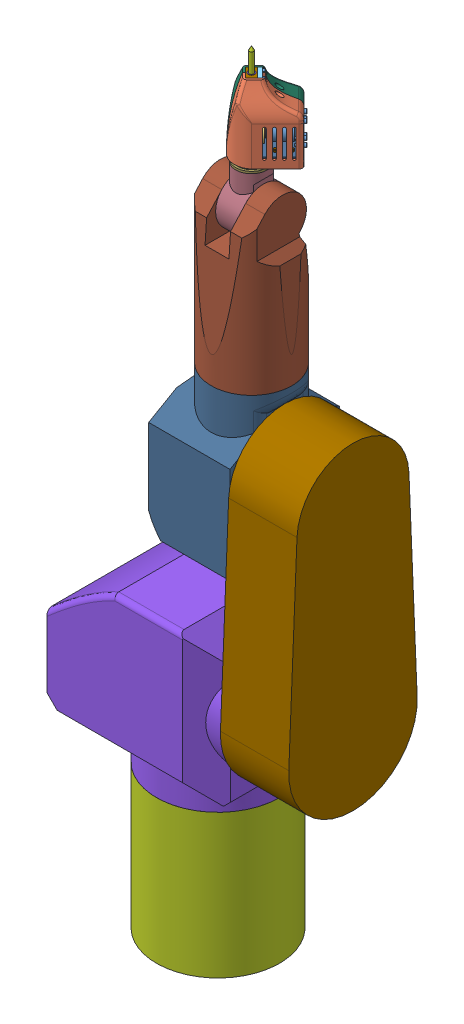
SolidWorks assembly Arm_2, configuration Default. Lengths in mm.
Overall size (341 1142 215.15).
59 component instances, 31 part files, 18 mates.
Components (placement in the parent):
- Assembly 1 _1_-1: Assembly 1 _1_ [Default] x (1 0 0) z (0 1 0) size (103.71 103.71 142.5)
  - Motor-1: Motor [Default] at (81.7405 32.7405 1038) x (0 0 1) z (-0.707107 0.707107 0) size (27.7 36 27.7)
  - MotorShaftMount-1: MotorShaftMount [Default] at (81.7405 32.7405 1038) x (0 0 1) z (-0.707107 0.707107 0) size (20 22.4 20)
  - MotorBearing-1: MotorBearing [Default] at (81.7405 32.7405 1038) x (0 0 1) z (-0.707107 0.707107 0) size (32 7 32)
  - MotorMount-1: MotorMount [Default] at (81.7405 32.7405 1038) x (0 0 1) z (-0.707107 0.707107 0) size (50 5 50)
  - ChiselBearingSupport-1: ChiselBearingSupport [Default] at (81.7405 32.7405 1038) x (0 0 1) z (-0.707107 0.707107 0) size (95.4 5 50)
  - ChiselOscillator-1: ChiselOscillator [Default] at (81.7405 32.7405 1038) x (0 0 1) z (-0.707107 0.707107 0) size (42 10.6 14)
  - Chisel-1: Chisel [Default] at (81.7405 32.7405 1038) x (0 0 1) z (-0.707107 0.707107 0) size (75 6.35 6.35)
  - SleeveBearingLarge-1: SleeveBearingLarge [Default] at (81.7405 32.7405 1038) x (0 0 1) z (-0.707107 0.707107 0) size (25.4 9.58 9.58)
  - ChiselShaftMount-1: ChiselShaftMount [Default] at (81.7405 32.7405 1038) x (0 0 1) z (-0.707107 0.707107 0) size (25.4 12.6 20)
  - BackSupport-1: BackSupport [Default] at (81.7405 32.7405 1038) x (0 0 1) z (-0.707107 0.707107 0) size (6 35 50)
  - FrontSupport-1: FrontSupport [Default] at (81.7405 32.7405 1038) x (0 0 1) z (-0.707107 0.707107 0) size (6 35 50)
  - 6mmBearing-1: 6mmBearing [Default] at (81.7405 32.7405 1038) x (0 0 1) z (-0.707107 0.707107 0) size (10 3 10)
  - 6mmBearing-2: 6mmBearing [Default] at (76.3636 27.3636 1038) x (0 0 1) z (-0.707107 0.707107 0) size (10 3 10)
  - Spacer-1: Spacer [Default] at (81.7405 32.7405 1038) x (0 0 1) z (-0.707107 0.707107 0) size (10 4.6 10)
  - SleeveBearingSmall-1: SleeveBearingSmall [Default] at (81.7405 32.7405 1038) x (0 0 1) z (-0.707107 0.707107 0) size (6.35 3.17 6.35)
  - SleeveBearingSmall-2: SleeveBearingSmall [Default] at (76.4874 27.4874 1038) x (0 0 1) z (-0.707107 0.707107 0) size (6.35 3.17 6.35)
  - ShellUpper-1: ShellUpper [Default] at (81.7405 32.7405 1038) x (0 0 1) z (-0.707107 0.707107 0) size (102.4 83.19 31.74)
  - MountingPlate-1: MountingPlate [Default] at (81.7405 32.7405 1038) x (0 0 1) z (-0.707107 0.707107 0) size (7 74.3 46)
  - Hex socket head cap screw ISO 4762-1: Hex socket head cap screw ISO 4762 [Default] at (60.1369 11.1369 1012.5) x (0.707107 0.707107 0) z (0 0 1) size (8.5 8.5 13)
  - Hex socket head cap screw ISO 4762-2: Hex socket head cap screw ISO 4762 [Default] at (37.8631 -11.1369 1012.5) x (0.707107 0.707107 0) z (0 0 1) size (8.5 8.5 13)
  - Hex socket head cap screw ISO 4762-3: Hex socket head cap screw ISO 4762 [Default] at (37.8631 11.1369 1012.5) x (0.707107 0.707107 0) z (0 0 1) size (8.5 8.5 13)
  - Hex socket head cap screw ISO 4762-4: Hex socket head cap screw ISO 4762 [Default] at (60.1369 -11.1369 1012.5) x (0.707107 0.707107 0) z (0 0 1) size (8.5 8.5 13)
  - Hex socket head cap screw ISO 4762-1-1: Hex socket head cap screw ISO 4762-1 [Default] at (56.41 27.209 1001) x (0.707107 0.707107 0) z (0 0 -1) size (8.5 8.5 21)
  - Hex socket head cap screw ISO 4762-1-2: Hex socket head cap screw ISO 4762-1 [Default] at (88.6861 19.8871 1001) x (0.707107 0.707107 0) z (0 0 -1) size (8.5 8.5 21)
  - Hex socket head cap screw ISO 4762-1-3: Hex socket head cap screw ISO 4762-1 [Default] at (68.8871 39.6861 1001) x (0.707107 0.707107 0) z (0 0 -1) size (8.5 8.5 21)
  - Hex socket head cap screw ISO 4762-1-4: Hex socket head cap screw ISO 4762-1 [Default] at (76.209 7.41 1001) x (0.707107 0.707107 0) z (0 0 -1) size (8.5 8.5 21)
  - Hex socket head cap screw ISO 4762-2-1: Hex socket head cap screw ISO 4762-2 [Default] at (71.841 53.9537 1016) x (0 0 1) z (0.707107 0.707107 0) size (5.5 5.5 13)
  - Hex socket head cap screw ISO 4762-2-2: Hex socket head cap screw ISO 4762-2 [Default] at (77.1443 52.893 1038) x (0 0 1) z (0.707107 0.707107 0) size (5.5 5.5 13)
  - Hex socket head cap screw ISO 4762-2-3: Hex socket head cap screw ISO 4762-2 [Default] at (54.1633 15.0628 1105.4) x (0 0 1) z (0.707107 0.707107 0) size (5.5 5.5 13)
  - Hex socket head cap screw ISO 4762-2-4: Hex socket head cap screw ISO 4762-2 [Default] at (83.3314 46.7058 1053.1554) x (0 0 1) z (0.707107 0.707107 0) size (5.5 5.5 13)
  - Hex socket head cap screw ISO 4762-2-5: Hex socket head cap screw ISO 4762-2 [Default] at (64.0628 5.1633 1086) x (0 0 1) z (0.707107 0.707107 0) size (5.5 5.5 13)
  - Hex socket head cap screw ISO 4762-2-6: Hex socket head cap screw ISO 4762-2 [Default] at (83.3314 46.7058 1022.8446) x (0 0 1) z (0.707107 0.707107 0) size (5.5 5.5 13)
  - Hex socket head cap screw ISO 4762-2-7: Hex socket head cap screw ISO 4762-2 [Default] at (64.0628 5.1633 1105.4) x (0 0 1) z (0.707107 0.707107 0) size (5.5 5.5 13)
  - Hex socket head cap screw ISO 4762-2-8: Hex socket head cap screw ISO 4762-2 [Default] at (101.893 28.1443 1038) x (0 0 1) z (0.707107 0.707107 0) size (5.5 5.5 13)
  - Hex socket head cap screw ISO 4762-2-9: Hex socket head cap screw ISO 4762-2 [Default] at (54.1633 15.0628 1086) x (0 0 1) z (0.707107 0.707107 0) size (5.5 5.5 13)
  - Hex socket head cap screw ISO 4762-2-10: Hex socket head cap screw ISO 4762-2 [Default] at (95.7058 34.3314 1053.1554) x (0 0 1) z (0.707107 0.707107 0) size (5.5 5.5 13)
  - Hex socket head cap screw ISO 4762-2-11: Hex socket head cap screw ISO 4762-2 [Default] at (35.7785 17.8912 1060) x (0 0 1) z (-0.707107 -0.707107 0) size (5.5 5.5 13)
  - Hex socket head cap screw ISO 4762-2-12: Hex socket head cap screw ISO 4762-2 [Default] at (95.7058 34.3314 1022.8446) x (0 0 1) z (0.707107 0.707107 0) size (5.5 5.5 13)
  - Hex socket head cap screw ISO 4762-2-13: Hex socket head cap screw ISO 4762-2 [Default] at (66.8912 -13.2215 1060) x (0 0 1) z (-0.707107 -0.707107 0) size (5.5 5.5 13)
  - Hex socket head cap screw ISO 4762-2-14: Hex socket head cap screw ISO 4762-2 [Default] at (102.9537 22.841 1016) x (0 0 1) z (0.707107 0.707107 0) size (5.5 5.5 13)
  - Hex socket head cap screw ISO 4762-2-15: Hex socket head cap screw ISO 4762-2 [Default] at (66.8912 -13.2215 1016) x (0 0 1) z (-0.707107 -0.707107 0) size (5.5 5.5 13)
  - Hex socket head cap screw ISO 4762-2-16: Hex socket head cap screw ISO 4762-2 [Default] at (35.7785 17.8912 1016) x (0 0 1) z (-0.707107 -0.707107 0) size (5.5 5.5 13)
  - Hex socket head cap screw ISO 4762-2-17: Hex socket head cap screw ISO 4762-2 [Default] at (102.9537 22.841 1060) x (0 0 1) z (0.707107 0.707107 0) size (5.5 5.5 13)
  - Hex socket head cap screw ISO 4762-2-18: Hex socket head cap screw ISO 4762-2 [Default] at (71.841 53.9537 1060) x (0 0 1) z (0.707107 0.707107 0) size (5.5 5.5 13)
  - ShellLower-1: ShellLower [Default] at (81.7405 32.7405 1038) x (0 0 1) z (-0.707107 0.707107 0) size (102.4 83.19 31.74)
  - Hex socket head cap screw ISO 4762-3-1: Hex socket head cap screw ISO 4762-3 [Default] at (57.8498 1.4768 1041.01) x (0 0 1) z (-0.707107 -0.707107 0) size (3.8 3.8 10)
  - Hex socket head cap screw ISO 4762-3-2: Hex socket head cap screw ISO 4762-3 [Default] at (54.1633 5.1633 1031.98) x (0 0 1) z (-0.707107 -0.707107 0) size (3.8 3.8 10)
  - Hex socket head cap screw ISO 4762-3-3: Hex socket head cap screw ISO 4762-3 [Default] at (50.4768 8.8498 1041.01) x (0 0 1) z (-0.707107 -0.707107 0) size (3.8 3.8 10)
  - BearingRetainingRing-1: BearingRetainingRing [Default] at (45.0034 -3.9966 1040) x (0.707107 0.707107 0) z (0 0 1) size (0.7 9.6 7.72)
  - HeadedPin-1: HeadedPin [Default] at (48.4835 -0.5165 1070) x (-0.707107 -0.707107 0) z (0 0 1) size (15.88 5.21 5.21)
  - ChiselPinSmallRR-1: ChiselPinSmallRR [Default] at (45.1611 -3.8389 1070) x (-0.707107 -0.707107 0) z (0 0 -1) size (0.25 3.57 4.47)
- Part 1-1: Part 1 [Default] x (1 0 0) z (0 1 0) size (180 180 210)
- Part 2-1: Part 2 [Default] x (1 0 0) z (0 1 0) size (241 215.15 243)
- Part 3-1: Part 3 [Default] x (1 0 0) z (0 1 0) size (100 188 466)
- Part 4-1: Part 4 [Default] x (1 0 0) z (0 1 0) size (136.5 160 240)
- Part 5-1: Part 5 [Default] x (1 0 0) z (0 1 0) size (118 118 235)
- Part 6-1: Part 6 [Default] x (1 0 0) z (0 1 0) size (46 46 9.5)
- Part 7-1: Part 7 [Default] x (1 0 0) z (0 1 0) size (46 70 90.5)
Mates (geometry in assembly coordinates):
- Coincident1: coincident anti-aligned: plane of Part 1-1 through (0 210 0) normal (0 1 0); plane of Part 2-1 through (0 210 0) normal (0 -1 0)
- Concentric1: concentric aligned: cylinder of Part 1-1 through (0 210 0) axis (0 -1 0) radius 90; cylinder of Part 2-1 through (0 260 0) axis (0 -1 0) radius 90
- Coincident2: coincident anti-aligned: plane of Part 2-1 through (97.5 341 0) normal (1 0 0); plane of Part 3-1 through (97.5 480 0) normal (-1 0 0)
- Concentric2: concentric aligned: cylinder of Part 2-1 through (97.5 341 0) axis (-1 0 0) radius 90; cylinder of Part 3-1 through (197.5 341 0) axis (-1 0 0) radius 94
- Coincident3: coincident anti-aligned: plane of Part 3-1 through (97.5 480 0) normal (-1 0 0); plane of Part 4-1 through (97.5 504 0) normal (1 0 0)
- Concentric3: concentric anti-aligned: circle of Part 3-1; circle of Part 4-1
- Coincident4: coincident anti-aligned: plane of Part 4-1 through (-28.5 741 -74.641) normal (0 1 0); plane of Part 5-1 through (49 741 0) normal (0 -1 0)
- Concentric4: concentric anti-aligned: cylinder of Part 4-1 through (49 691 0) axis (0 1 0) radius 59; cylinder of Part 5-1 through (49 976 0) axis (0 -1 0) radius 59
- Coincident5: coincident anti-aligned: plane of Part 5-1 through (31.5 941 -1056.0159) normal (1 0 0); plane of Part 7-1 through (31.5 941 -1056.0159) normal (-1 0 0)
- Concentric5: concentric anti-aligned: cylinder of Part 5-1 through (-1056.0159 941 0) axis (1 0 0) radius 35; cylinder of Part 7-1 through (66.502 941 0) axis (-1 0 0) radius 35
- Coincident7: coincident anti-aligned: plane of Part 6-1 through (49 996.5 0) normal (0 -1 0); plane of Part 7-1 through (49 996.5 0) normal (0 1 0)
- Concentric6: concentric aligned: cylinder of Part 6-1 through (49 905.998 0) axis (0 1 0) radius 23; cylinder of Part 7-1 through (49 905.998 0) axis (0 1 0) radius 23
- Concentric7: concentric aligned: cylinder of Assembly 1 _1_-1/Hex socket head cap screw ISO 4762-1 through (60.1369 1006 -11.1369) axis (0 1 0) radius 2.5; cylinder of Part 6-1 through (60.1369 999.5 -11.1369) axis (0 1 0) radius 2.5
- Concentric8: concentric aligned: cylinder of Assembly 1 _1_-1/Hex socket head cap screw ISO 4762-4 through (60.1369 1006 11.1369) axis (0 1 0) radius 2.5; cylinder of Part 6-1 through (60.1369 999.5 11.1369) axis (0 1 0) radius 2.5
- Coincident10: coincident anti-aligned: plane of Assembly 1 _1_-1/MountingPlate-1 through (59.0063 1006 -10.0063) normal (0 -1 0); plane of Part 6-1 through (49 1006 0) normal (0 1 0)
- Coincident11: coincident anti-aligned: plane of Part 1-1 through (0 0 0) normal (0 -1 0); plane of assembly through (0 0 0) normal (0 1 0)
- Coincident12: coincident anti-aligned: plane of Part 1-1 through (0 0 0) normal (0 0 -1); plane of assembly through (0 0 0) normal (0 0 1)
- Coincident13: coincident aligned: plane of Part 1-1 through (0 0 0) normal (1 0 0); plane of assembly through (0 0 0) normal (1 0 0)
